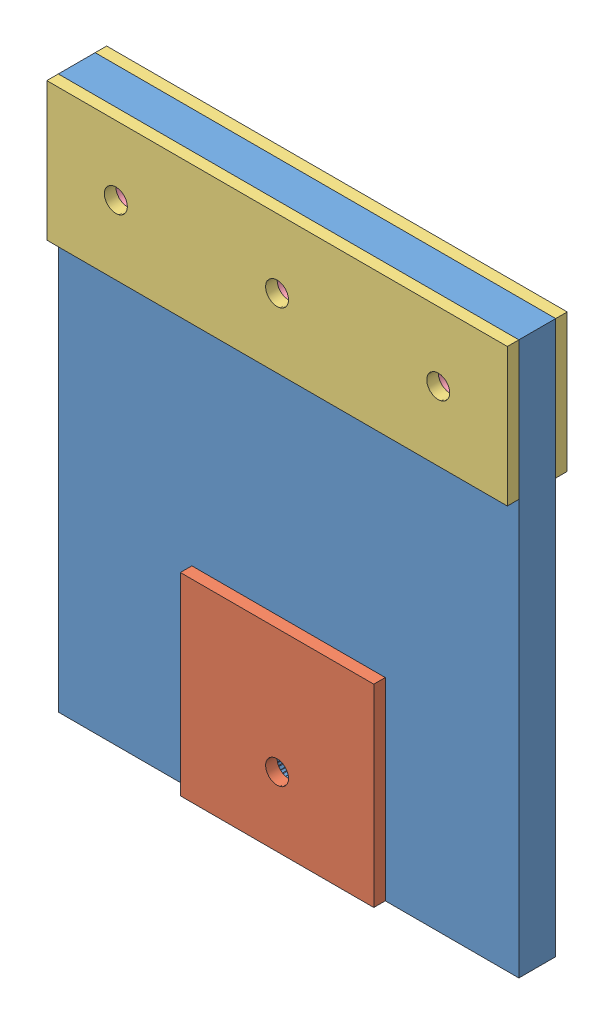
SolidWorks assembly Supported Pullthrough Test, configuration Default. Lengths in mm.
Overall size (127 152.4 16.51).
9 component instances, 4 part files, 12 mates.
Components (placement in the parent):
- Carbon Coupon-1: Carbon Coupon [Default] at (30.6326 45.1315 154.2043) size (127 152.4 10.16)
- Part20^Supported Pullthrough Test-1: Part20^Supported Pullthrough Test [Default] at (30.6326 45.1315 164.3643) size (53.34 53.34 3.17) (virtual)
- Tie down Bracket-1: Tie down Bracket [Default] at (30.6326 45.1315 164.3643) size (127 38.1 3.17)
- Tie down Bracket-2: Tie down Bracket [Default] at (30.6326 45.1315 151.0293) size (127 38.1 3.17)
- Part20^Supported Pullthrough Test-2: Part20^Supported Pullthrough Test [Default] at (30.6326 45.1315 151.0293) size (53.34 53.34 3.17) (virtual)
- Insert-1: Insert [Default] at (94.1326 64.1815 154.2043) x (1 0 0) z (0 -1 0) size (12.7 10.16 12.7)
- Insert-2: Insert [Default] at (49.6826 178.4815 154.2043) x (1 0 0) z (0 -1 0) size (12.7 10.16 12.7)
- Insert-3: Insert [Default] at (94.1326 178.4815 154.2043) x (1 0 0) z (0 -1 0) size (12.7 10.16 12.7)
- Insert-4: Insert [Default] at (138.5826 178.4815 154.2043) x (1 0 0) z (0 -1 0) size (12.7 10.16 12.7)
Mates (geometry in assembly coordinates):
- InPlace1: in place: plane of Carbon Coupon-1 through (30.6326 45.1315 164.3643) normal (0 0 1); plane of ? through (0 0 164.3643) normal (0 0 1); moOrthogonalPlaneRef_w of Carbon Coupon-1 through (30.6326 45.1315 164.3643) normal (0 0 1); plane of ? through (0 0 164.3643) normal (0 1 0); plane of Carbon Coupon-1 through (30.6326 45.1315 164.3643) normal (0 0 1); plane of ? through (0 0 164.3643) normal (1 0 0); plane of Carbon Coupon-1 through (30.6326 45.1315 164.3643) normal (0 0 1); unknown of ?
- Coincident1: coincident aligned: plane of ?; plane of ?
- Coincident2: coincident aligned: moOrthogonalPlaneRef_w of Carbon Coupon-1 through (30.6326 45.1315 164.3643) normal (0 1 0); plane of Part20^Assem2-1 through (30.6326 45.1315 164.3643) normal (0 1 0)
- Coincident3: coincident anti-aligned: moOrthogonalPlaneRef_w of Carbon Coupon-1 through (30.6326 45.1315 164.3643) normal (-1 0 0); plane of Part20^Assem2-1 through (30.6326 45.1315 164.3643) normal (1 0 0)
- InPlace2: in place: plane of Carbon Coupon-1 through (30.6326 45.1315 164.3643) normal (0 0 1); plane of ? through (0 0 164.3643) normal (0 0 1); plane of Carbon Coupon-1 through (30.6326 45.1315 164.3643) normal (0 0 1); plane of ? through (0 0 164.3643) normal (0 1 0); plane of Carbon Coupon-1 through (30.6326 45.1315 164.3643) normal (0 0 1); plane of ? through (0 0 164.3643) normal (1 0 0); plane of Carbon Coupon-1 through (30.6326 45.1315 164.3643) normal (0 0 1); unknown of ?
- Coincident4: coincident aligned: plane of ?; plane of ?
- Coincident5: coincident aligned: moOrthogonalPlaneRef_w of Carbon Coupon-1 through (30.6326 45.1315 164.3643) normal (0 1 0); plane of Part21^Assem2-1 through (30.6326 45.1315 164.3643) normal (0 1 0)
- Coincident6: coincident anti-aligned: moOrthogonalPlaneRef_w of Carbon Coupon-1 through (30.6326 45.1315 164.3643) normal (-1 0 0); plane of Part21^Assem2-1 through (30.6326 45.1315 164.3643) normal (1 0 0)
- Concentric1: concentric aligned: circle of Carbon Coupon-1; circle of Insert-1
- Coincident7: coincident aligned: circle of Part21^Supported Pullthrough Test-1; circle of Insert-2
- Coincident8: coincident aligned: circle of Part21^Supported Pullthrough Test-1; circle of Insert-3
- Coincident9: coincident aligned: circle of Part21^Supported Pullthrough Test-1; circle of Insert-4
